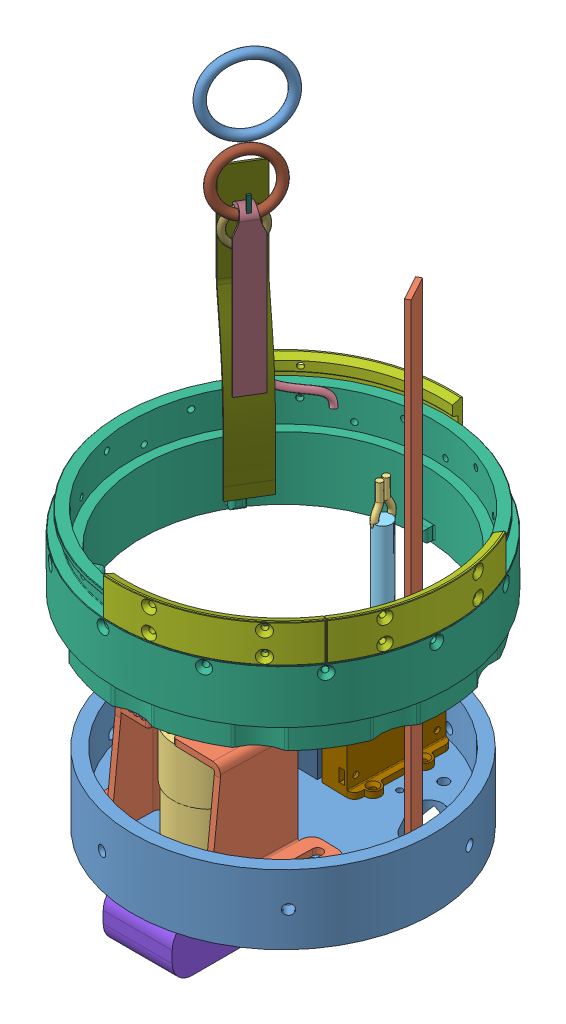
SolidWorks assembly Assem3.2, configuration Default. Lengths in mm.
Overall size (208.08 332.54 208.08).
44 component instances, 35 part files, 55 mates.
Components (placement in the parent):
- lower_ring_V3-1: lower_ring_V3 [Default] at (-435.8517 -102.3465 7.7829) size (168.91 136.61 168.91) (hidden)
- twist_coupling_V3-1: twist_coupling_V3 [Default] at (-435.8517 -107.3964 7.7829) x (0.733162 0 -0.680054) z (0.680054 0 0.733162) size (151.13 30.48 151.13) (hidden)
- keeper_assy_V3-1: keeper_assy_V3 [Default] at (-398.3126 -234.2766 -121.2195) x (0.853602 0 0.520926) z (-0.520926 0 0.853602) size (151.38 85 151.38)
  - keeper_ring_V3-2: keeper_ring_V3 [Default] at (35.1573 70.992 129.6717) size (151.38 34.92 151.38)
  - motor_bracket_sheetmetal_V3-3: motor_bracket_sheetmetal_V3 [Default] at (75.2187 124.967 148.1443) x (-0.5 0 -0.866025) z (0.866025 0 -0.5) size (49.21 53.98 88.82)
  - BLDC_Gear_Motor_100rpm-1: BLDC_Gear_Motor_100rpm [Default] at (53.2217 96.792 160.8443) x (-0.930418 0 -0.366501) z (0.366501 0 -0.930418) size (37 68.5 37)
  - 7880K450_HT-LOAD MTL GEAR--20 DEG PRESSURE ANGLE-1: 7880K450_HT-LOAD MTL GEAR--20 DEG PRESSURE ANGLE [7880K45] at (50.6562 142.366 167.3572) x (-0.827633 0 -0.561269) z (0 1 0) size (1219.2 52.9 14.26)
- Linear_actuator-2: Linear_actuator [Default] at (-434.8197 -203.3126 -33.2592) x (-0.999704 0 -0.024335) z (0.024335 0 -0.999704) size (20 138 36)
- upper_ring_V3-1: upper_ring_V3 [Default] at (-435.8517 -87.8081 7.7829) x (-0.999728 0 -0.02334) z (0.02334 0 -0.999728) size (168.91 49.11 168.91)
- tube_ring_V3-1: tube_ring_V3 [Default] at (-435.8517 -53.6425 7.7829) x (-0.430589 0 -0.902548) z (0.902548 0 -0.430589) size (151.13 25.4 151.13) (hidden)
- moduleRing_flat-3: moduleRing_flat [Default] at (-435.8517 -25.9176 7.7829) x (0.902548 0 -0.430589) z (0.430589 0 0.902548) size (168.91 17.36 168.91) (hidden)
- Nose_cone_whole-1: Nose_cone_whole [Default] at (-427.313 -12.6611 -67.9372) x (0 -1 0) z (0.993702 0 0.112057) size (934.42 175.32 175.32) (hidden)
- clampArc-1: clampArc [Default] at (-435.8517 -26.8981 7.7829) x (0.902548 0 -0.430589) z (-0.430589 0 -0.902548) size (83.87 18.8 15.42)
- clampArc-2: clampArc [Default] at (-435.8517 -45.702 7.7829) x (-0.824175 0 -0.566335) z (0.566335 0 -0.824175) size (83.87 18.8 15.42) (hidden)
- clampArc-3: clampArc [Default] at (-435.8517 -45.702 7.7829) x (-0.078373 0 0.996924) z (-0.996924 0 -0.078373) size (83.87 18.8 15.42)
- clampArc-4: clampArc [Default] at (-435.8517 -45.702 7.7829) x (0.824175 0 0.566335) z (-0.566335 0 0.824175) size (83.87 18.8 15.42) (hidden)
- clampArc-5: clampArc [Default] at (-435.8517 -45.702 7.7829) x (0.078373 0 -0.996924) z (0.996924 0 0.078373) size (83.87 18.8 15.42) (hidden)
- clampArc-6: clampArc [Default] at (-435.8517 -45.702 7.7829) x (0.902548 0 -0.430589) z (0.430589 0 0.902548) size (83.87 18.8 15.42)
- Cylinder_Chute_Main^ERS_v0.3-1: Cylinder_Chute_Main^ERS_v0.3 [Default] at (-435.8517 -68.0346 7.7829) x (-0.520926 0 0.853602) z (-0.853602 0 -0.520926) size (136.63 325.15 116.84) (hidden)
- Cup_Chute_Drogue^ERS_v0.2-1: Cup_Chute_Drogue^ERS_v0.2 [Default] at (-435.8517 249.4654 7.7829) x (0.939861 0 -0.341556) z (0 1 0) size (117.77 117.77 365.12) (hidden)
- ST_Bottom-1: ST_Bottom [Default] at (-435.8517 606.9704 7.7829) x (0.99648 0 -0.083828) z (0.083828 0 0.99648) size (90.93 12.7 90.93) (hidden)
- ST_Cap-1: ST_Cap [Default] at (-435.8517 599.348 7.7829) x (0.975096 0 -0.221784) z (0.221784 0 0.975096) size (90.93 5.08 90.93) (hidden)
- PIZZA_v3.0_split-1: PIZZA_v3.0_split [Default] at (-435.8517 -74.3846 7.7829) x (0.999704 0 0.024335) z (-0.024335 0 0.999704) size (116.82 98.43 114.78) (hidden)
- battery-1: battery [Default] at (-437.6063 -189.0656 5.6372) x (1 0 0) z (0 -1 0) size (34.8 73.66 26.16)
- LinAct_Bracket_Back-1: LinAct_Bracket_Back [Default] at (-436.6344 -163.2846 8.2244) x (0.840672 0 0.541544) z (0 1 0) size (38.9 48.74 33.02)
- LinAct_Bracket_Front-1: LinAct_Bracket_Front [Default] at (-436.6344 -163.2846 8.2244) x (0.840672 0 0.541544) z (0 1 0) size (38.02 48.74 33.02)
- 3-ring_assy_V1-1: 3-ring_assy_V1 [Default] at (-475.2789 134.7452 -15.3776) x (0 1 0) z (0.520926 0 -0.853602) size (479.53 98.88 39.69)
  - H3860S_NO3_Ring-1: H3860S_NO3_Ring [Default] at (-51.3677 -8.0145 0) x (0 0 1) z (0.109189 0.994021 0) size (31.35 31.35 4.56)
  - H3880S_NO4_Ring-1: H3880S_NO4_Ring [Default] at (-78.0917 -10.3227 0) x (0 0 1) z (0 1 0) size (20.24 20.24 3.37)
  - webbing_base_V1-1: webbing_base_V1 [Default] at (-148.7292 0 0) x (1 0 0) z (0 0 -1) size (226.78 20.16 15.88) (hidden)
  - webbing_small_V1-2: webbing_small_V1 [Default] at (-116.3544 -1.524 0) x (1 0 0) z (0 0 -1) size (81.41 12.13 12.7)
  - yellow_cord_V1.1-1: yellow_cord_V1.1 [Default] at (-205.5518 -5.8886 0) x (0 1 0) z (0 0 -1) size (98.88 160.58 9.08)
  - nylon_loop_V1-1: nylon_loop_V1 [Default] at (-91.6172 -16.6947 0) x (0 0 1) z (0 -1 0) size (4.82 25.4 15.18)
  - grommet_assy-1: grommet_assy [Default] at (-227.0655 159.1333 21.2356) x (0 0 -1) z (0 -1 0) size (19.05 139.7 16.13)
    - webbing_grommet_V1-1: webbing_grommet_V1 [Default] at (21.2356 27.4983 171.1427) size (19.05 139.7 11.24)
    - grommet_V1-1: grommet_V1 [Default] at (21.2356 135.4483 170.5712) x (1 0 0) z (0 -1 0) size (10.16 2.6 10.16)
    - yellow_cord_guide-1: yellow_cord_guide [Default] at (21.2356 159.2608 174.1907) x (1 0 0) z (0 -1 0) size (18.04 4.89 15.88)
  - H3840B_NO2_Ring-1: H3840B_NO2_Ring [Default] at (-25.4211 -5.2162 0) x (0.999637 -0.026926 0) z (0.026926 0.999637 0) size (39.69 39.69 4.76)
  - webbing_top_V1-3: webbing_top_V1 [Default] at (100.8035 -5.7956 0) size (226.82 8.38 15.88) (hidden)
  - yellow_cord_guide-2: yellow_cord_guide [Default] at (-97.9672 -15.0574 0) x (0 0 -1) z (-1 0 0) size (18.04 4.89 15.88)
- webbing_base_V2-1: webbing_base_V2 [Default] at (-475.4077 -14.1767 -15.1666) x (0 1 0) z (-0.520926 0 0.853602) size (270.89 13.99 15.88) (hidden)
- ShockCordMain-1: ShockCordMain [Default] at (-392.2016 -99.896 -16.0623) x (0.478777 0 0.877936) z (-0.877936 0 0.478777) size (14.29 254 2.54)
- yellow_cord_short-1: yellow_cord_short [Default] at (-435.7042 -48.7121 -44.0591) size (3.17 23.4 12)
- yellow_twist-1: yellow_twist [Default] at (-485.5497 -32.8678 -17.0479) x (-0.970601 0 -0.240695) z (0.239826 -0.084902 -0.967096) size (3.3 46.88 45.21)
Mates (geometry in assembly coordinates):
- Concentric6: concentric anti-aligned: cylinder of lower_ring_V3-1 through (-435.8517 -102.3465 7.7829) axis (0 1 0) radius 76.2; cylinder of keeper_assy_V3-1/keeper_ring_V3-2 through (-435.8517 -141.0596 7.7829) axis (0 -1 0) radius 75.692
- Concentric11: concentric aligned: circle of twist_coupling_V3-1; circle of lower_ring_V3-1
- Coincident4: coincident anti-aligned: plane of lower_ring_V3-1 through (-435.8517 -91.8389 -68.4171) normal (0 -1 0); plane of twist_coupling_V3-1 through (-383.7092 -91.8389 -40.5826) normal (0 1 0)
- Concentric13: concentric aligned: circle of lower_ring_V3-1; circle of upper_ring_V3-1
- Coincident13: coincident anti-aligned: plane of keeper_assy_V3-1/keeper_ring_V3-2 through (-435.8517 -163.2846 7.7829) normal (0 1 0); plane of ? through (-433.8076 -163.4102 -33.7857) normal (0 -1 0)
- Concentric20: concentric aligned: circle of upper_ring_V3-1; circle of tube_ring_V3-1
- Concentric21: concentric anti-aligned: cylinder of upper_ring_V3-1 through (-483.6815 -49.8579 77.3886) axis (-0.566335 0 0.824175) radius 1.4732; cylinder of tube_ring_V3-1 through (-499.8645 -49.8579 100.9394) axis (0.566335 0 -0.824175) radius 1.5
- Concentric22: concentric anti-aligned: circle of moduleRing_flat-3; circle of Nose_cone_whole-1
- Coincident23: coincident anti-aligned: plane of moduleRing_flat-3 through (-360.544 -19.0111 -28.1451) normal (0 1 0); plane of Nose_cone_whole-1 through (-427.313 -19.0111 -67.9372) normal (0 -1 0)
- Coincident24: coincident anti-aligned: circle of upper_ring_V3-1; circle of moduleRing_flat-3
- Coincident30: coincident aligned: plane of clampArc-1 through (-435.8517 -26.8981 7.7829) normal (0 1 0); plane of clampArc-2 through (-435.8517 -26.8981 7.7829) normal (0 1 0)
- Tangent10: tangent aligned: cylinder of clampArc-1 through (-435.8517 -84.0517 7.7829) axis (0 -1 0) radius 79.6; cylinder of clampArc-2 through (-435.8517 11.4517 7.7829) axis (0 1 0) radius 79.6
- Concentric37: concentric aligned: circle of moduleRing_flat-3; circle of clampArc-1
- Parallel15: parallel anti-aligned: plane of clampArc-1 through (-435.6618 -45.702 7.7978) normal (-0.996924 0 -0.078373); plane of clampArc-2 through (-436.0416 -26.8981 7.7679) normal (0.996924 0 0.078373)
- Parallel16: parallel anti-aligned: plane of clampArc-1 through (-435.9596 -45.702 7.9399) normal (0.566335 0 -0.824175); plane of clampArc-3 through (-435.7438 -26.8981 7.6259) normal (-0.566335 0 0.824175)
- Coincident33: coincident aligned: circle of clampArc-1; circle of clampArc-3
- Concentric38: concentric aligned: circle of clampArc-3; circle of clampArc-4
- Parallel17: parallel anti-aligned: plane of clampArc-3 through (-435.7697 -26.8981 7.9548) normal (-0.430589 0 -0.902548); plane of clampArc-4 through (-435.9338 -26.8981 7.6109) normal (0.430589 0 0.902548)
- Coincident36: coincident aligned: cone of clampArc-3 through (-435.8517 -45.702 7.7829) axis (0 1 0); cone of clampArc-4 through (-435.8517 -45.702 7.7829) axis (0 1 0)
- Concentric39: concentric aligned: cone of clampArc-2 through (-435.8517 -45.702 7.7829) axis (0 1 0); cone of clampArc-5 through (-435.8517 -45.702 7.7829) axis (0 1 0)
- Parallel18: parallel anti-aligned: plane of clampArc-2 through (-435.7697 -26.8981 7.9548) normal (-0.430589 0 -0.902548); plane of clampArc-5 through (-435.9338 -26.8981 7.6109) normal (0.430589 0 0.902548)
- Coincident39: coincident aligned: circle of clampArc-2; circle of clampArc-5
- Coincident42: coincident aligned: cone of clampArc-5 through (-435.8517 -26.8981 7.7829) axis (0 -1 0); cone of clampArc-6 through (-435.8517 -26.8981 7.7829) axis (0 -1 0)
- Parallel19: parallel anti-aligned: plane of clampArc-5 through (-435.9596 -26.8981 7.9399) normal (0.566335 0 -0.824175); plane of clampArc-6 through (-435.7438 -26.8981 7.6259) normal (-0.566335 0 0.824175)
- Concentric43: concentric aligned: cylinder of moduleRing_flat-3 through (-409.4207 -30.5731 -66.8766) axis (0.333725 0 -0.94267) radius 1.524; cylinder of clampArc-4 through (-407.667 -30.5731 -71.8304) axis (0.333725 0 -0.94267) radius 1.4732
- Parallel25: parallel aligned: cylinder of upper_ring_V3-1 through (-409.4207 -42.1769 -66.8766) axis (0.333725 0 -0.94267) radius 1.524; cylinder of clampArc-4 through (-407.667 -42.027 -71.8304) axis (0.333725 0 -0.94267) radius 1.4732
- Concentric47: concentric: unknown of ?; unknown of Cylinder_Chute_Main^ERS_v0.3-1
- Coincident53: coincident anti-aligned: plane of Cylinder_Chute_Main^ERS_v0.3-1 through (-435.8517 249.4654 7.7829) normal (0 1 0); plane of ? through (-485.6466 249.4753 -22.7682) normal (0 -1 0)
- Coincident55: coincident anti-aligned: circle of ST_Bottom-1; circle of ST_Cap-1
- Concentric49: concentric: circle of ?; circle of ST_Bottom-1
- Coincident56: coincident: plane of ? through (-435.8517 614.6003 7.7829) normal (0 1 0); plane of ST_Bottom-1 through (-435.8517 614.5904 7.7829) normal (0 -1 0)
- Concentric50: concentric anti-aligned: circle of keeper_assy_V3-1/keeper_ring_V3-2; circle of PIZZA_v3.0-1
- Coincident57: coincident anti-aligned: plane of keeper_assy_V3-1/keeper_ring_V3-2 through (-435.8517 -163.2846 7.7829) normal (0 1 0); plane of PIZZA_v3.0-1 through (-457.8155 -163.2846 -27.9109) normal (0 -1 0)
- Parallel29: parallel aligned: plane of keeper_assy_V3-1/keeper_ring_V3-2 through (-480.9312 -175.9846 -7.6393) normal (-0.853602 0 -0.520926); plane of PIZZA_v3.0-1 through (-475.5288 -68.0346 -16.4308) normal (-0.853602 0 -0.520926)
- Parallel30: parallel aligned: plane of Cylinder_Chute_Main^ERS_v0.3-1 through (-474.8784 -68.0346 -16.0339) normal (-0.853602 0 -0.520926); plane of PIZZA_v3.0-1 through (-475.5288 -68.0346 -16.4308) normal (-0.853602 0 -0.520926)
- Parallel31: parallel aligned: cylinder of lower_ring_V3-1 through (-374.6328 -158.5139 65.9627) axis (0.72487 0 0.688886) radius 3.2639; cylinder of keeper_assy_V3-1/keeper_ring_V3-2 through (-380.9849 -158.3883 59.926) axis (0.72487 0 0.688886) radius 2.5527
- Coincident60: coincident anti-aligned: plane of keeper_assy_V3-1/keeper_ring_V3-2 through (-435.8517 -175.9846 7.7829) normal (0 -1 0); plane of battery-1 through (-455.0053 -175.9846 79.2972) normal (0 1 0)
- Coincident64: coincident anti-aligned: plane of keeper_assy_V3-1/keeper_ring_V3-2 through (-435.8517 -163.2846 7.7829) normal (0 1 0); plane of LinAct_Bracket_Back-1 through (-436.6344 -163.2846 8.2244) normal (0 -1 0)
- Coincident65: coincident anti-aligned: plane of keeper_assy_V3-1/keeper_ring_V3-2 through (-435.8517 -163.2846 7.7829) normal (0 1 0); plane of LinAct_Bracket_Front-1 through (-436.6344 -163.2846 8.2244) normal (0 -1 0)
- Coincident67: coincident anti-aligned: plane of Linear_actuator-2 through (-444.3787 -133.3126 -51.4972) normal (-0.999704 0 -0.024335); plane of LinAct_Bracket_Front-1 through (-444.3787 -160.2366 -51.4972) normal (0.999704 0 0.024335)
- Coincident68: coincident anti-aligned: plane of Linear_actuator-2 through (-425.2607 -133.3126 -15.0212) normal (-0.024335 0 0.999704); plane of LinAct_Bracket_Front-1 through (-445.2547 -160.2366 -15.5078) normal (0.024335 0 -0.999704)
- Coincident69: coincident anti-aligned: plane of Linear_actuator-2 through (-424.3846 -133.3126 -51.0105) normal (0.999704 0 0.024335); plane of LinAct_Bracket_Back-1 through (-425.2607 -160.2366 -15.0212) normal (-0.999704 0 -0.024335)
- Coincident70: coincident anti-aligned: plane of Linear_actuator-2 through (-425.2607 -133.3126 -15.0212) normal (-0.024335 0 0.999704); plane of LinAct_Bracket_Back-1 through (-445.2547 -160.2366 -15.5078) normal (0.024335 0 -0.999704)
- Coincident71: coincident anti-aligned: plane of Linear_actuator-2 through (-434.8197 -133.3126 -33.2592) normal (0 1 0); plane of LinAct_Bracket_Front-1 through (-436.6344 -133.3126 8.2244) normal (0 -1 0)
- Concentric51: concentric anti-aligned: circle of PIZZA_v3.0-1; circle of Cylinder_Chute_Main^ERS_v0.3-1
- Concentric52: concentric anti-aligned: circle of Cylinder_Chute_Main^ERS_v0.3-1; circle of Cup_Chute_Drogue^ERS_v0.2-1
- Coincident72: coincident anti-aligned: plane of Cylinder_Chute_Main^ERS_v0.3-1 through (-435.8517 249.4654 7.7829) normal (0 1 0); plane of Cup_Chute_Drogue^ERS_v0.2-1 through (-455.9641 249.4654 -47.5604) normal (0 -1 0)
- Coincident73: coincident anti-aligned: plane of ST_Bottom-1 through (-435.8517 614.5904 7.7829) normal (0 -1 0); plane of Cup_Chute_Drogue^ERS_v0.2-1 through (-435.8517 614.5904 7.7829) normal (0 1 0)
- Concentric53: concentric aligned: circle of ST_Bottom-1; circle of Cup_Chute_Drogue^ERS_v0.2-1
- Coincident74: coincident anti-aligned: plane of Cylinder_Chute_Main^ERS_v0.3-1 through (-435.8517 -68.0346 7.7829) normal (0 -1 0); plane of PIZZA_v3.0-1 through (-435.8517 -68.0346 7.7829) normal (0 1 0)
- Coincident75: coincident anti-aligned: plane of lower_ring_V3-1 through (-435.8517 -85.4889 -63.6546) normal (0 1 0); plane of upper_ring_V3-1 through (-516.6017 -85.4889 5.8976) normal (0 -1 0)
- Coincident78: coincident anti-aligned: plane of Cylinder_Chute_Main^ERS_v0.3-1 through (-474.8784 -68.0346 -16.0339) normal (-0.853602 0 -0.520926); plane of 3-ring_assy_V1-1/webbing_base_V1-1 through (-475.2789 -13.984 -15.3776) normal (0.853602 0 0.520926)
- Parallel33: parallel anti-aligned: line of Cylinder_Chute_Main^ERS_v0.3-1 through (-470.9908 132.2727 -26.5174) axis (0 1 0); line of 3-ring_assy_V1-1/webbing_top_V1-3 through (-484.3609 336.9885 -11.6213) axis (0 -1 0)
- Coincident80: coincident anti-aligned: plane of Cylinder_Chute_Main^ERS_v0.3-1 through (-474.8784 -68.0346 -16.0339) normal (-0.853602 0 -0.520926); plane of webbing_base_V2-1 through (-475.4077 -14.1767 -15.1666) normal (0.853602 0 0.520926)
- Parallel34: parallel aligned: line of Cylinder_Chute_Main^ERS_v0.3-1 through (-485.932 -68.0346 2.0788) axis (0 1 0); line of webbing_base_V2-1 through (-479.5425 -174.8753 -8.3912) axis (0 1 0)
